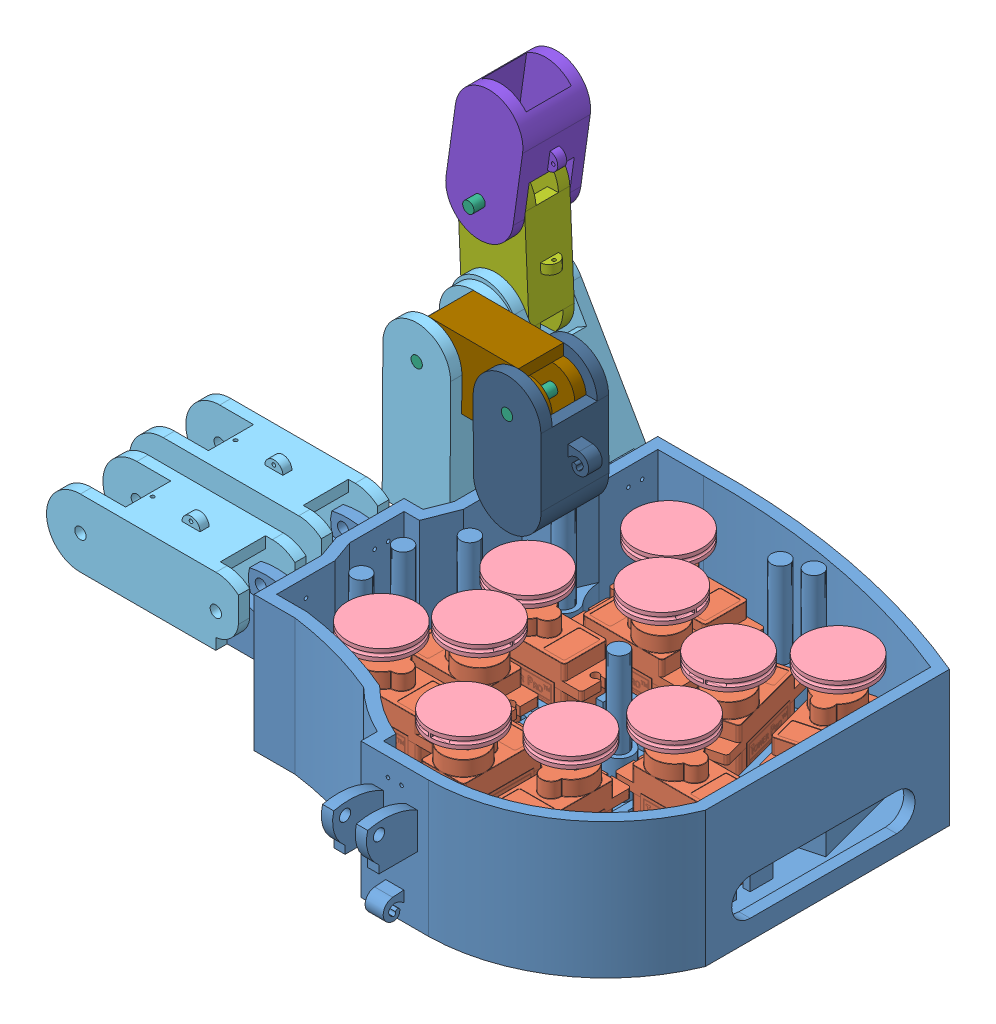
SolidWorks assembly hand-assembly, configuration Default. Lengths in mm.
Overall size (176.55 119.82 130.32).
55 component instances, 10 part files, 55 mates.
Components (placement in the parent):
- palm-1: palm [Default] at (5.8833 -35.3199 72.5354) size (132.65 38.1 130.32)
- servo-spinner-combo-1: servo-spinner-combo [Default] at (-31.7523 -33.025 78.5509) size (32.1 34.93 19.05)
  - SG90 - Micro Servo 9g - Tower Pro.1-1: SG90 - Micro Servo 9g - Tower Pro.1 [Peça] at (12.6007 11.4301 24.99) size (32.1 29.95 12.4)
  - SG90 - Micro Servo 9g - Tower Pro.3-1: SG90 - Micro Servo 9g - Tower Pro.3 [Peça] at (7.4507 32.5301 24.99) x (0.379808 0 -0.925065) z (0.925065 0 0.379808) size (14.96 3.8 6.9)
  - fishing-line-spinner-375-1: fishing-line-spinner-375 [Default] at (7.4507 32.5301 24.99) size (19.05 3.17 19.05)
- servo-spinner-combo-2: servo-spinner-combo [Default] at (-4.0108 -33.025 113.7683) x (-1 0 0) z (0 0 -1) size (32.1 34.93 19.05)
  - SG90 - Micro Servo 9g - Tower Pro.1-1: SG90 - Micro Servo 9g - Tower Pro.1 [Peça] at (12.6007 11.4301 24.99) size (32.1 29.95 12.4)
  - SG90 - Micro Servo 9g - Tower Pro.3-1: SG90 - Micro Servo 9g - Tower Pro.3 [Peça] at (7.4507 32.5301 24.99) x (0.379808 0 -0.925065) z (0.925065 0 0.379808) size (14.96 3.8 6.9)
  - fishing-line-spinner-375-1: fishing-line-spinner-375 [Default] at (7.4507 32.5301 24.99) size (19.05 3.17 19.05)
- servo-spinner-combo-3: servo-spinner-combo [Default] at (-24.1323 -33.025 45.0229) size (32.1 34.93 19.05)
  - SG90 - Micro Servo 9g - Tower Pro.1-1: SG90 - Micro Servo 9g - Tower Pro.1 [Peça] at (12.6007 11.4301 24.99) size (32.1 29.95 12.4)
  - SG90 - Micro Servo 9g - Tower Pro.3-1: SG90 - Micro Servo 9g - Tower Pro.3 [Peça] at (7.4507 32.5301 24.99) x (0.379808 0 -0.925065) z (0.925065 0 0.379808) size (14.96 3.8 6.9)
  - fishing-line-spinner-375-1: fishing-line-spinner-375 [Default] at (7.4507 32.5301 24.99) size (19.05 3.17 19.05)
- servo-spinner-combo-4: servo-spinner-combo [Default] at (13.7692 -33.025 80.2709) x (-1 0 0) z (0 0 -1) size (32.1 34.93 19.05)
  - SG90 - Micro Servo 9g - Tower Pro.1-1: SG90 - Micro Servo 9g - Tower Pro.1 [Peça] at (12.6007 11.4301 24.99) size (32.1 29.95 12.4)
  - SG90 - Micro Servo 9g - Tower Pro.3-1: SG90 - Micro Servo 9g - Tower Pro.3 [Peça] at (7.4507 32.5301 24.99) x (0.379808 0 -0.925065) z (0.925065 0 0.379808) size (14.96 3.8 6.9)
  - fishing-line-spinner-375-1: fishing-line-spinner-375 [Default] at (7.4507 32.5301 24.99) size (19.05 3.17 19.05)
- servo-spinner-combo-5: servo-spinner-combo [Default] at (-13.9723 -33.025 15.5589) size (32.1 34.93 19.05)
  - SG90 - Micro Servo 9g - Tower Pro.1-1: SG90 - Micro Servo 9g - Tower Pro.1 [Peça] at (12.6007 11.4301 24.99) size (32.1 29.95 12.4)
  - SG90 - Micro Servo 9g - Tower Pro.3-1: SG90 - Micro Servo 9g - Tower Pro.3 [Peça] at (7.4507 32.5301 24.99) x (0.379808 0 -0.925065) z (0.925065 0 0.379808) size (14.96 3.8 6.9)
  - fishing-line-spinner-375-1: fishing-line-spinner-375 [Default] at (7.4507 32.5301 24.99) size (19.05 3.17 19.05)
- servo-spinner-combo-6: servo-spinner-combo [Default] at (-16.3255 -33.025 120.8544) x (0 0 -1) z (1 0 0) size (32.1 34.93 19.05)
  - SG90 - Micro Servo 9g - Tower Pro.1-1: SG90 - Micro Servo 9g - Tower Pro.1 [Peça] at (12.6007 11.4301 24.99) size (32.1 29.95 12.4)
  - SG90 - Micro Servo 9g - Tower Pro.3-1: SG90 - Micro Servo 9g - Tower Pro.3 [Peça] at (7.4507 32.5301 24.99) x (0.379808 0 -0.925065) z (0.925065 0 0.379808) size (14.96 3.8 6.9)
  - fishing-line-spinner-375-1: fishing-line-spinner-375 [Default] at (7.4507 32.5301 24.99) size (19.05 3.17 19.05)
- servo-spinner-combo-7: servo-spinner-combo [Default] at (53.5935 -33.025 95.653) x (0 0 1) z (-1 0 0) size (32.1 34.93 19.05)
  - SG90 - Micro Servo 9g - Tower Pro.1-1: SG90 - Micro Servo 9g - Tower Pro.1 [Peça] at (12.6007 11.4301 24.99) size (32.1 29.95 12.4)
  - SG90 - Micro Servo 9g - Tower Pro.3-1: SG90 - Micro Servo 9g - Tower Pro.3 [Peça] at (7.4507 32.5301 24.99) x (0.379808 0 -0.925065) z (0.925065 0 0.379808) size (14.96 3.8 6.9)
  - fishing-line-spinner-375-1: fishing-line-spinner-375 [Default] at (7.4507 32.5301 24.99) size (19.05 3.17 19.05)
- servo-spinner-combo-8: servo-spinner-combo [Default] at (31.9348 -33.025 59.7549) size (32.1 34.93 19.05)
  - SG90 - Micro Servo 9g - Tower Pro.1-1: SG90 - Micro Servo 9g - Tower Pro.1 [Peça] at (12.6007 11.4301 24.99) size (32.1 29.95 12.4)
  - SG90 - Micro Servo 9g - Tower Pro.3-1: SG90 - Micro Servo 9g - Tower Pro.3 [Peça] at (7.4507 32.5301 24.99) x (0.379808 0 -0.925065) z (0.925065 0 0.379808) size (14.96 3.8 6.9)
  - fishing-line-spinner-375-1: fishing-line-spinner-375 [Default] at (7.4507 32.5301 24.99) size (19.05 3.17 19.05)
- servo-spinner-combo-9: servo-spinner-combo [Default] at (9.6751 -33.025 75.732) x (-0.258819 0 -0.965926) z (0.965926 0 -0.258819) size (32.1 34.93 19.05)
  - SG90 - Micro Servo 9g - Tower Pro.1-1: SG90 - Micro Servo 9g - Tower Pro.1 [Peça] at (12.6007 11.4301 24.99) size (32.1 29.95 12.4)
  - SG90 - Micro Servo 9g - Tower Pro.3-1: SG90 - Micro Servo 9g - Tower Pro.3 [Peça] at (7.4507 32.5301 24.99) x (0.379808 0 -0.925065) z (0.925065 0 0.379808) size (14.96 3.8 6.9)
  - fishing-line-spinner-375-1: fishing-line-spinner-375 [Default] at (7.4507 32.5301 24.99) size (19.05 3.17 19.05)
- servo-spinner-combo-10: servo-spinner-combo [Default] at (69.9954 -33.025 33.4788) x (0.258819 0 0.965926) z (-0.965926 0 0.258819) size (32.1 34.93 19.05)
  - SG90 - Micro Servo 9g - Tower Pro.1-1: SG90 - Micro Servo 9g - Tower Pro.1 [Peça] at (12.6007 11.4301 24.99) size (32.1 29.95 12.4)
  - SG90 - Micro Servo 9g - Tower Pro.3-1: SG90 - Micro Servo 9g - Tower Pro.3 [Peça] at (7.4507 32.5301 24.99) x (0.379808 0 -0.925065) z (0.925065 0 0.379808) size (14.96 3.8 6.9)
  - fishing-line-spinner-375-1: fishing-line-spinner-375 [Default] at (7.4507 32.5301 24.99) size (19.05 3.17 19.05)
- finger-base-1: finger-base [Default] at (-49.8551 -16.2699 115.0267) x (0 0 -1) z (1 0 0) size (19.05 21.59 53.98)
- finger-base-2: finger-base [Default] at (-51.9471 -16.2699 89.6267) x (0 0 -1) z (1 0 0) size (19.05 21.59 53.98)
- finger-base-3: finger-base [Default] at (-63.4321 -16.0895 64.2267) x (0 0 -1) z (-0.005028 -0.999987 0) size (19.05 21.59 53.98)
- finger-base-4: finger-base [Default] at (-44.591 -19.7552 38.8267) x (0 0 -1) z (0.499733 -0.866179 0) size (19.05 21.59 53.98)
- metal-connector-1: metal-connector [Default] at (-41.1006 -6.7449 19.7767) x (1 0.000037 0) z (0 0 1) size (3.17 3.17 19.05)
- finger-mid-joint-1: finger-mid-joint [Default] at (-70.2766 39.7897 29.3017) x (0.04442 -0.999013 0) z (0 0 1) size (40.64 21.59 12.7)
- metal-connector-2: metal-connector [Default] at (-60.1404 26.2565 19.7767) x (0.999961 -0.008783 0) z (0 0 1) size (3.17 3.17 19.05)
- metal-connector-3: metal-connector [Default] at (-61.3815 54.169 22.9517) x (0.944462 0.328622 0) z (0 0 1) size (3.17 3.17 19.05)
- finger-tip-2: finger-tip [Default] at (-69.0477 68.0702 29.3017) x (0.139076 0.990282 0) z (0 0 -1) size (38.1 26.67 19.05)
- finger-mid-joint-shorter-1: finger-mid-joint-shorter [Default] at (-40.934 40.9668 54.7017) x (-0.999994 0.003557 0) z (0 0 1) size (38.1 21.59 12.7)
- finger-tip-bigger-hook-1: finger-tip-bigger-hook [Default] at (-18.7017 18.7277 54.7017) x (0.00325 -0.999995 0) z (0 0 -1) size (38.1 27.39 19.05)
- metal-connector-4: metal-connector [Default] at (-53.8593 -6.6125 45.1767) size (3.17 3.17 19.05)
- metal-connector-5: metal-connector [Default] at (-53.6678 31.487 45.1767) size (3.17 3.17 19.05)
- metal-connector-6: metal-connector [Default] at (-28.2679 31.3967 45.1767) size (3.17 3.17 19.05)
Mates (geometry in assembly coordinates):
- Coincident2: coincident: plane of palm-1 through (-10.7386 -32.1449 221.7613) normal (0 1 0); plane of servo-spinner-combo-1/SG90 - Micro Servo 9g - Tower Pro.1-1 through (-29.5515 -32.1449 108.7909) normal (0 -1 0)
- Coincident3: coincident: plane of palm-1 through (-10.7386 -32.1449 221.7613) normal (0 1 0); plane of servo-spinner-combo-8/SG90 - Micro Servo 9g - Tower Pro.1-1 through (34.1355 -32.1449 89.9949) normal (0 -1 0)
- Coincident4: coincident: plane of palm-1 through (-10.7386 -32.1449 221.7613) normal (0 1 0); plane of servo-spinner-combo-2/SG90 - Micro Servo 9g - Tower Pro.1-1 through (-6.2115 -32.1449 83.5283) normal (0 -1 0)
- Coincident5: coincident: plane of palm-1 through (-10.7386 -32.1449 221.7613) normal (0 1 0); plane of servo-spinner-combo-3/SG90 - Micro Servo 9g - Tower Pro.1-1 through (-21.9315 -32.1449 75.2629) normal (0 -1 0)
- Coincident6: coincident: plane of palm-1 through (-10.7386 -32.1449 221.7613) normal (0 1 0); plane of servo-spinner-combo-4/SG90 - Micro Servo 9g - Tower Pro.1-1 through (11.5685 -32.1449 50.0309) normal (0 -1 0)
- Coincident7: coincident: plane of palm-1 through (-10.7386 -32.1449 221.7613) normal (0 1 0); plane of servo-spinner-combo-5/SG90 - Micro Servo 9g - Tower Pro.1-1 through (-11.7715 -32.1449 45.7989) normal (0 -1 0)
- Coincident8: coincident: plane of palm-1 through (-10.7386 -32.1449 221.7613) normal (0 1 0); plane of servo-spinner-combo-6/SG90 - Micro Servo 9g - Tower Pro.1-1 through (13.9145 -32.1449 118.6537) normal (0 -1 0)
- Coincident9: coincident: plane of palm-1 through (-10.7386 -32.1449 221.7613) normal (0 1 0); plane of servo-spinner-combo-7/SG90 - Micro Servo 9g - Tower Pro.1-1 through (23.3535 -32.1449 97.8537) normal (0 -1 0)
- Coincident10: coincident: plane of palm-1 through (-10.7386 -32.1449 221.7613) normal (0 1 0); plane of servo-spinner-combo-9/SG90 - Micro Servo 9g - Tower Pro.1-1 through (38.3151 -32.1449 65.7796) normal (0 -1 0)
- Coincident11: coincident: plane of palm-1 through (-10.7386 -32.1449 221.7613) normal (0 1 0); plane of servo-spinner-combo-10/SG90 - Micro Servo 9g - Tower Pro.1-1 through (41.3554 -32.1449 43.4312) normal (0 -1 0)
- Distance1: distance = 0 mm: plane of finger-base-1 through (-49.8551 2.7801 115.0267) normal (0 1 0); plane of palm-1 through (-10.7386 2.7801 221.7613) normal (0 1 0)
- Distance2: distance = 0 mm: plane of finger-base-2 through (-51.9471 2.7801 89.6267) normal (0 1 0); plane of palm-1 through (-10.7386 2.7801 221.7613) normal (0 1 0)
- Coincident16: coincident: plane of palm-1 through (-30.3056 -22.6199 35.6517) normal (0 0 1); plane of finger-base-4 through (-68.9201 54.1809 35.6517) normal (0 0 -1)
- Distance5: distance = 0 mm: plane of metal-connector-1 through (-41.1006 -6.7449 19.7767) normal (0 0 -1); plane of finger-base-4 through (-28.0903 -10.2353 19.7767) normal (0 0 -1)
- Distance6: distance = 0 mm: cylinder of finger-base-4 through (-41.1006 -6.7449 19.7767) axis (0 0 1) radius 1.5875; cylinder of metal-connector-1 through (-41.1006 -6.7449 38.8267) axis (0 0 -1) radius 1.5875
- Coincident18: coincident: plane of palm-1 through (-50.8842 -22.6199 86.4517) normal (0 0 1); plane of finger-base-2 through (-128.1471 -0.3949 86.4517) normal (0 0 -1)
- Coincident19: coincident: plane of palm-1 through (-43.0643 -22.6199 61.0517) normal (0 0 1); plane of finger-base-3 through (-47.1742 60.0297 61.0517) normal (0 0 -1)
- Coincident20: coincident: plane of palm-1 through (-48.6206 -22.6199 111.8517) normal (0 0 1); plane of finger-base-1 through (-126.0551 -0.3949 111.8517) normal (0 0 -1)
- Distance7: distance = 0.254 mm: plane of servo-spinner-combo-1/SG90 - Micro Servo 9g - Tower Pro.1-1 through (-29.5515 -16.4449 109.6409) normal (0 0 1); plane of palm-1 through (-7.0125 -21.3499 109.8949) normal (0 0 -1)
- Distance8: distance = 0.889 mm: plane of servo-spinner-combo-1/SG90 - Micro Servo 9g - Tower Pro.1-1 through (-7.9015 -16.4449 108.7909) normal (1 0 0); plane of palm-1 through (-7.0125 -21.3499 101.6399) normal (-1 0 0)
- Distance10: distance = 0.889 mm: plane of servo-spinner-combo-2/SG90 - Micro Servo 9g - Tower Pro.1-1 through (-5.3615 -32.1449 83.5283) normal (1 0 0); plane of palm-1 through (-4.4725 -21.3499 86.9079) normal (-1 0 0)
- Distance11: distance = 0.254 mm: plane of servo-spinner-combo-3/SG90 - Micro Servo 9g - Tower Pro.1-1 through (-21.9315 -16.4449 76.1129) normal (0 0 1); plane of palm-1 through (0.6075 -21.3499 76.3669) normal (0 0 -1)
- Distance12: distance = 0.889 mm: plane of servo-spinner-combo-3/SG90 - Micro Servo 9g - Tower Pro.1-1 through (-0.2815 -32.1449 64.7629) normal (1 0 0); plane of palm-1 through (0.6075 -21.3499 63.6669) normal (-1 0 0)
- Distance13: distance = 0.254 mm: plane of servo-spinner-combo-4/SG90 - Micro Servo 9g - Tower Pro.1-1 through (11.5685 -16.4449 61.3809) normal (0 0 1); plane of palm-1 through (2.6395 -21.3499 61.6349) normal (0 0 -1)
- Distance14: distance = 0.889 mm: plane of servo-spinner-combo-4/SG90 - Micro Servo 9g - Tower Pro.1-1 through (12.4185 -16.4449 50.0309) normal (1 0 0); plane of palm-1 through (13.3075 -21.3499 48.9349) normal (-1 0 0)
- Distance15: distance = 0.889 mm: plane of servo-spinner-combo-5/SG90 - Micro Servo 9g - Tower Pro.1-1 through (9.8785 -16.4449 45.7989) normal (1 0 0); plane of palm-1 through (10.7675 -21.3499 34.2029) normal (-1 0 0)
- Distance17: distance = 0.254 mm: plane of servo-spinner-combo-6/SG90 - Micro Servo 9g - Tower Pro.1-1 through (14.7645 -16.4449 118.6537) normal (1 0 0); plane of palm-1 through (15.0185 -21.3499 96.1147) normal (-1 0 0)
- Distance18: distance = 0.889 mm: plane of servo-spinner-combo-6/SG90 - Micro Servo 9g - Tower Pro.1-1 through (3.4145 -32.1449 97.0037) normal (0 0 -1); plane of palm-1 through (2.3185 -21.3499 96.1147) normal (0 0 1)
- Distance19: distance = 0.889 mm: plane of servo-spinner-combo-7/SG90 - Micro Servo 9g - Tower Pro.1-1 through (23.3535 -16.4449 97.0037) normal (0 0 -1); plane of palm-1 through (22.2575 -21.3499 96.1147) normal (0 0 1)
- Distance20: distance = 0.254 mm: plane of servo-spinner-combo-7/SG90 - Micro Servo 9g - Tower Pro.1-1 through (34.7035 -16.4449 97.8537) normal (1 0 0); plane of palm-1 through (34.9575 -21.3499 96.1147) normal (-1 0 0)
- Distance21: distance = 0.889 mm: plane of servo-spinner-combo-8/SG90 - Micro Servo 9g - Tower Pro.1-1 through (55.7855 -32.1449 79.4949) normal (1 0 0); plane of palm-1 through (56.6745 -21.3499 78.3989) normal (-1 0 0)
- Distance22: distance = 0.254 mm: plane of servo-spinner-combo-8/SG90 - Micro Servo 9g - Tower Pro.1-1 through (34.1355 -16.4449 90.8449) normal (0 0 1); plane of palm-1 through (56.6745 -21.3499 91.0989) normal (0 0 -1)
- Distance23: distance = 0.889 mm: plane of servo-spinner-combo-9/SG90 - Micro Servo 9g - Tower Pro.1-1 through (38.5351 -32.1449 66.6006) normal (0.258819 0 0.965926); plane of palm-1 through (39.6249 -21.3499 67.229) normal (-0.258819 0 -0.965926)
- Distance26: distance = 0.889 mm: plane of servo-spinner-combo-10/SG90 - Micro Servo 9g - Tower Pro.1-1 through (57.1011 -32.1449 61.6259) normal (0.258819 0 0.965926); plane of palm-1 through (58.3938 -21.3499 62.1999) normal (-0.258819 0 -0.965926)
- Coincident21: coincident: plane of finger-base-4 through (-68.9201 54.1809 22.9517) normal (0 0 1); plane of finger-mid-joint-1 through (-95.0033 52.674 22.9517) normal (0 0 -1)
- Coincident22: coincident: plane of finger-base-4 through (-28.0903 -10.2353 19.7767) normal (0 0 -1); plane of metal-connector-2 through (-60.1404 26.2565 19.7767) normal (0 0 -1)
- Coincident24: coincident: plane of finger-mid-joint-1 through (-95.0033 52.674 22.9517) normal (0 0 -1); plane of metal-connector-3 through (-61.3815 54.169 22.9517) normal (0 0 -1)
- Concentric9: concentric: cylinder of metal-connector-3 through (-61.3815 54.169 42.0017) axis (0 0 -1) radius 1.5875; cylinder of finger-tip-2 through (-61.3815 54.169 38.8267) axis (0 0 -1) radius 1.5875
- Coincident26: coincident: plane of finger-mid-joint-1 through (-95.687 68.05 35.6517) normal (0 0 1); plane of finger-tip-2 through (-73.1254 39.0351 35.6517) normal (0 0 -1)
- Concentric10: concentric: cylinder of palm-1 through (-41.1006 -6.7449 38.8267) axis (0 0 -1) radius 1.5875; cylinder of metal-connector-1 through (-41.1006 -6.7449 38.8267) axis (0 0 -1) radius 1.5875
- Concentric14: concentric: cylinder of finger-mid-joint-1 through (-61.3815 54.169 19.7767) axis (0 0 1) radius 1.5875; cylinder of metal-connector-3 through (-61.3815 54.169 42.0017) axis (0 0 -1) radius 1.5875
- Concentric15: concentric: cylinder of finger-mid-joint-1 through (-60.1404 26.2565 19.7767) axis (0 0 1) radius 1.5875; cylinder of metal-connector-2 through (-60.1404 26.2565 38.8267) axis (0 0 -1) radius 1.5875
- Parallel2: parallel: cylinder of finger-base-4 through (-60.1404 26.2565 19.7767) axis (0 0 1) radius 1.5875; cylinder of metal-connector-2 through (-60.1404 26.2565 38.8267) axis (0 0 -1) radius 1.5875
- Concentric17: concentric: cylinder of finger-base-4 through (-60.1404 26.2565 19.7767) axis (0 0 1) radius 1.5875; cylinder of metal-connector-2 through (-60.1404 26.2565 38.8267) axis (0 0 -1) radius 1.5875
- Coincident28: coincident: plane of finger-base-3 through (-44.3824 -16.1853 45.1767) normal (0 0 -1); plane of metal-connector-4 through (-53.8593 -6.6125 45.1767) normal (0 0 -1)
- Concentric21: concentric: cylinder of palm-1 through (-53.8593 -6.6125 64.2267) axis (0 0 -1) radius 1.5875; cylinder of metal-connector-4 through (-53.8593 -6.6125 64.2267) axis (0 0 -1) radius 1.5875
- Concentric24: concentric: cylinder of finger-base-3 through (-53.8593 -6.6125 45.1767) axis (0 0 1) radius 1.5875; cylinder of metal-connector-4 through (-53.8593 -6.6125 64.2267) axis (0 0 -1) radius 1.5875
- Concentric25: concentric: cylinder of finger-base-3 through (-53.6678 31.487 45.1767) axis (0 0 1) radius 1.5875; cylinder of metal-connector-5 through (-53.6678 31.487 64.2267) axis (0 0 -1) radius 1.5875
- Coincident29: coincident: plane of finger-base-3 through (-44.3824 -16.1853 45.1767) normal (0 0 -1); plane of metal-connector-5 through (-53.6678 31.487 45.1767) normal (0 0 -1)
- Concentric26: concentric: cylinder of finger-mid-joint-shorter-1 through (-53.6678 31.487 45.1767) axis (0 0 1) radius 1.5875; cylinder of metal-connector-5 through (-53.6678 31.487 64.2267) axis (0 0 -1) radius 1.5875
- Coincident30: coincident: plane of finger-base-3 through (-47.1742 60.0297 48.3517) normal (0 0 1); plane of finger-mid-joint-shorter-1 through (-28.1482 65.0515 48.3517) normal (0 0 -1)
- Concentric27: concentric: cylinder of finger-mid-joint-shorter-1 through (-28.2679 31.3967 45.1767) axis (0 0 1) radius 1.5875; cylinder of metal-connector-6 through (-28.2679 31.3967 64.2267) axis (0 0 -1) radius 1.5875
- Coincident33: coincident: plane of finger-mid-joint-shorter-1 through (-11.4872 64.9922 61.0517) normal (0 0 1); plane of finger-tip-bigger-hook-1 through (-18.797 48.0476 61.0517) normal (0 0 -1)
- Coincident34: coincident: plane of finger-tip-bigger-hook-1 through (-37.8238 40.8907 64.2267) normal (0 0 1); plane of metal-connector-6 through (-28.2679 31.3967 64.2267) normal (0 0 1)
- Concentric29: concentric: cylinder of finger-tip-bigger-hook-1 through (-28.2679 31.3967 64.2267) axis (0 0 -1) radius 1.5875; cylinder of metal-connector-6 through (-28.2679 31.3967 64.2267) axis (0 0 -1) radius 1.5875
